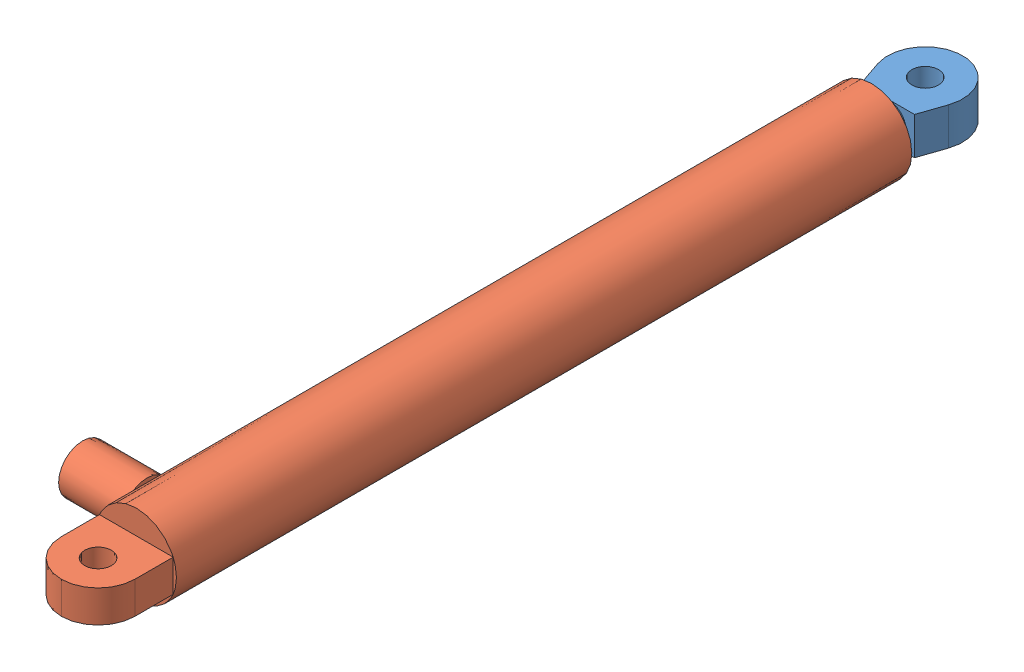
SolidWorks assembly hydraulic_cylinder_25CA, configuration Default. Lengths in mm.
Overall size (131.87 75 841).
2 component instances, 2 part files, 4 mates.
Components (placement in the parent):
- Cylinder_inside-1: Cylinder_inside [Default] at (0 0 664) x (0 -1 0) z (0 0 -1) size (35 70 749)
- Cylinder_outside-1: Cylinder_outside [Default] at origin size (131.87 75 756)
Mates (geometry in assembly coordinates):
- Concentric1: concentric anti-aligned: cylinder of Cylinder_inside-1 through (0 0 -515) axis (0 0 1) radius 17.5; cylinder of Cylinder_outside-1 through (0 0 664) axis (0 0 -1) radius 17.5
- Distance1: distance = 0 mm anti-aligned: plane of Cylinder_inside-1 through (0 0 664) normal (0 0 1); plane of Cylinder_outside-1 through (0 0 664) normal (0 0 -1)
- Parallel1: parallel anti-aligned: plane of Cylinder_inside-1 through (0 -17.5 -550) normal (0 -1 0); plane of Cylinder_outside-1 through (-34.3693 15 756) normal (0 1 0)
- Coincident9: coordinate: point of Cylinder_outside-1
